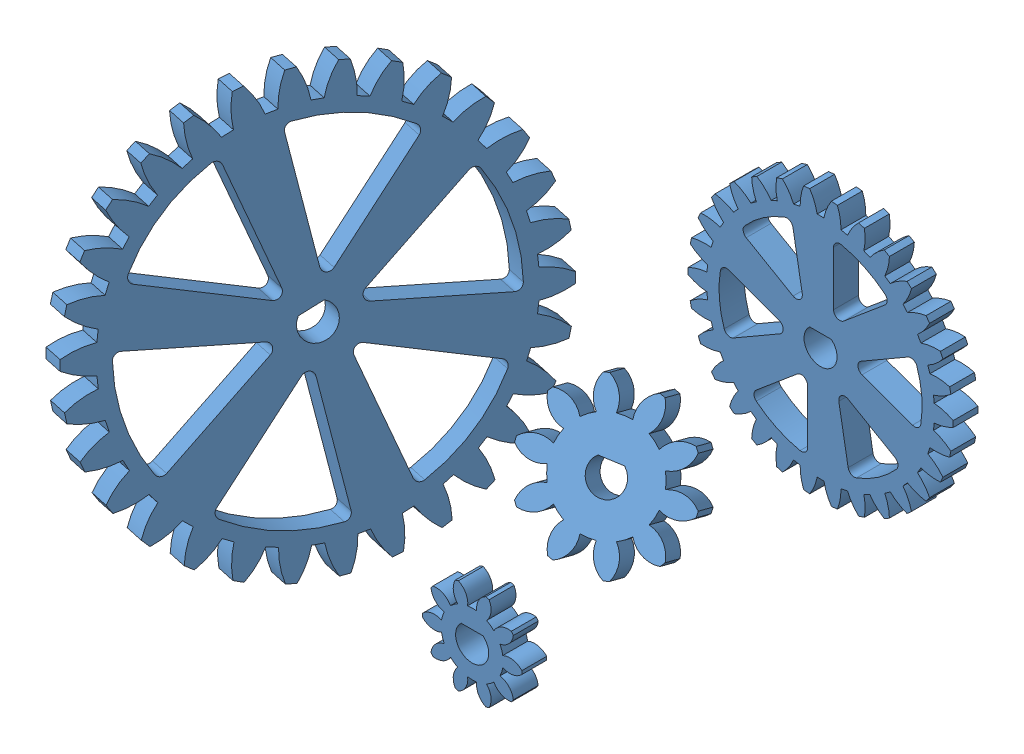
SolidWorks assembly gearsAssem, configuration Default. Lengths in mm.
Overall size (72.15 60.29 55.93).
4 component instances, 1 part files, 0 mates.
Components (placement in the parent):
- root_gear-1: root_gear [10T 1.0Mod] at (-5.2495 -9.3916 23.4798) size (12 11.53 3)
- root_gear-2: root_gear [30T 1.0Mod] at (12.2759 18.0828 -1.028) size (32 31.89 3)
- root_gear-3: root_gear [10T 1.5Mod] at (-0.874 3.8883 12.867) x (0.962946 -0.085155 -0.255899) z (0.267483 0.422843 0.865827) size (18 17.3 3)
- root_gear-4: root_gear [30T 1.5Mod] at (-27.5045 11.3439 22.8353) x (-0.278059 -0.320246 0.905608) z (-0.915608 -0.196684 -0.350682) size (48 47.84 3)
